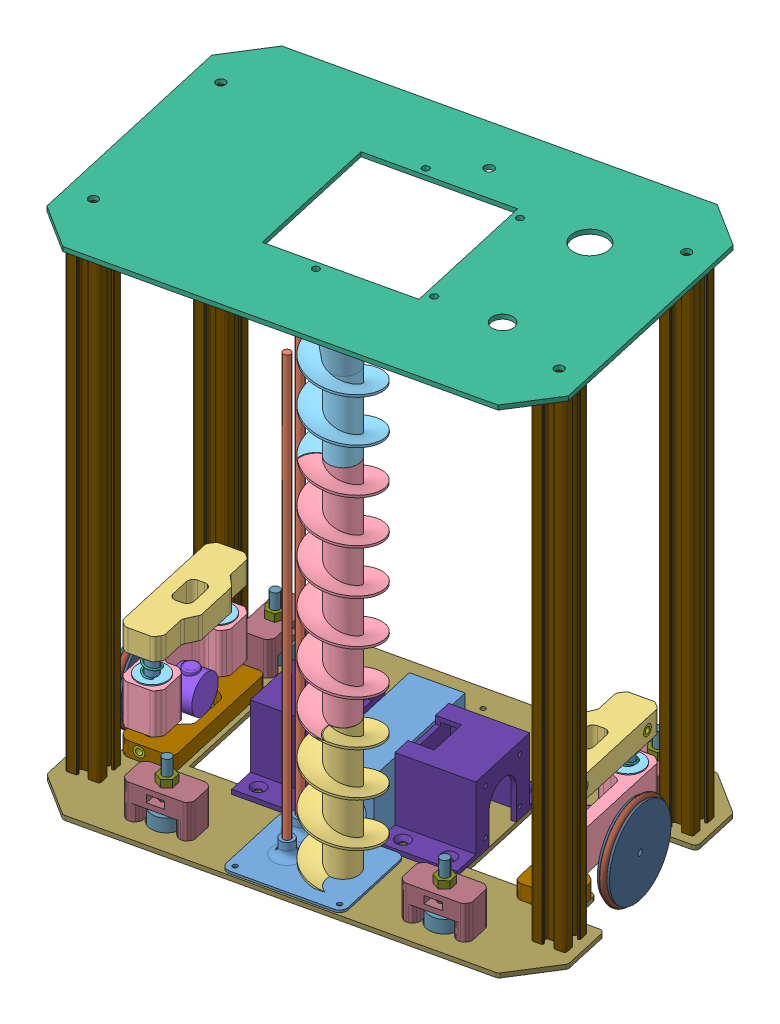
SolidWorks assembly Assemblage Robot 2 2023, configuration Défaut. Lengths in mm.
Overall size (336.15 361.9 260.69).
91 component instances, 24 part files, 26 mates.
Components (placement in the parent):
- Assemblage Base Roulante Robot 2-1: Assemblage Base Roulante Robot 2 [Défaut] at (-74.2511 215.8465 283.5318) size (336.15 94.74 260.69)
  - Assemblage Systeme Encodeurs-1: Assemblage Systeme Encodeurs [Défaut] at (-67.7934 10.2849 22.5399) size (62.28 94.74 89.05)
    - Axe_Support_Codeurs-1: Axe_Support_Codeurs [Défaut] at (-9.7273 -8.3238 48.8402) size (8 72 8)
    - Roulement linéaire-1: Roulement linéaire [Défaut] at (-9.7273 34.3589 48.8402) x (-0.971705 0 -0.236196) z (0 -1 0) size (15 15 24)
    - Support Ressort-1: Support Ressort [Défaut] at (-3.1044 51.6762 78.1001) x (0.220763 0 0.975327) z (-0.975327 0 0.220763) size (84.1 15.1 30.1)
    - Axe_Support_Codeurs-2: Axe_Support_Codeurs [Défaut] at (3.5185 -8.3238 107.3599) x (-0.166467 0 0.986047) z (-0.986047 0 -0.166467) size (8 72 8)
    - Roulement linéaire-2: Roulement linéaire [Défaut] at (3.5185 34.3589 107.3599) x (0.932325 0 -0.361623) z (0 -1 0) size (15 15 24)
    - Support Encodeurs-1: Support Encodeurs [Défaut] at (-3.1044 9.3589 78.1001) x (0.220763 0 0.975327) z (-0.975327 0 0.220763) size (84.1 37.8 24.1)
    - Rondelle M8-1: Rondelle M8 [Défaut] at (-9.7273 34.3589 48.8402) x (-0.837169 0 -0.546944) z (0 1 0) size (20 20 0.7)
    - Rondelle M8-2: Rondelle M8 [Défaut] at (3.5185 34.3589 107.3599) x (1 0 0) z (0 1 0) size (20 20 0.7)
    - Ressort M8-1: Ressort M8 [Défaut] at (3.5185 28.0864 107.3599) x (0.192743 0 -0.981249) z (0.981249 0 0.192743) size (12.72 24.18 12.45)
    - Ressort M8-2: Ressort M8 [Défaut] at (-9.7273 28.0864 48.8402) x (0.56484 0 0.8252) z (-0.8252 0 0.56484) size (12.72 24.18 12.45)
    - Insert M4-1: Insert M4 [Défaut] at (-21.1553 59.1762 52.7086) x (0.101832 0.887257 0.449894) z (0.975327 0 -0.220763) size (7 7 8)
    - Insert M4-4: Insert M4 [Défaut] at (-8.4614 59.1762 108.7899) x (0.099396 0.892908 0.439131) z (0.975327 0 -0.220763) size (7 7 8)
    - Codeurs Kuebler D24-2: Codeurs Kuebler D24 [Défaut] at (8.1118 8.8589 75.5613) x (-0.220763 0 -0.975327) z (-0.975327 0 0.220763) size (24 26 30.5)
    - Support Plaque Encodeurs-1: Support Plaque Encodeurs [Défaut] at (-3.1044 -10.3238 78.1001) x (0.220763 0 0.975327) z (-0.975327 0 0.220763) size (84 10 32)
    - Insert M4-5: Insert M4 [Défaut] at (6.1676 -4.8238 119.0638) x (-0.669085 -0.727591 0.151446) z (-0.220763 0 -0.975327) size (7 7 8)
    - Insert M4-6: Insert M4 [Défaut] at (-12.3765 -4.8238 37.1363) x (-0.897415 -0.391644 0.203128) z (0.220763 0 0.975327) size (7 7 8)
    - Insert M4-7: Insert M4 [Défaut] at (17.3015 -10.3238 109.3666) x (0.445123 0 0.895469) z (0 1 0) size (7 7 8)
    - Insert M4-8: Insert M4 [Défaut] at (1.8481 -10.3238 41.0937) x (0.956517 0 -0.291677) z (0 1 0) size (7 7 8)
    - Assemblage Roue Codeuse-1: Assemblage Roue Codeuse [Défaut] at (12.9164 -13.0885 115.5563) x (-0.212881 0.264817 -0.940507) z (0.975327 0 -0.220763) size (60 60 17)
      - Roue folle D56 BRS-1: Roue folle D56 BRS [Défaut] at (44.4504 10.553 -33.3566) size (56 56 17)
      - Joint Torique D52 T4 BRS-1: Joint Torique D52 T4 BRS [Défaut] at (44.4504 10.553 -29.8566) size (60 60 4)
  - Assemblage Systeme Encodeurs-2: Assemblage Systeme Encodeurs [Défaut] at (155.6849 10.2849 126.7509) x (-1 0 0) z (0 0 -1) size (62.28 94.74 89.05)
    - Axe_Support_Codeurs-1: Axe_Support_Codeurs [Défaut] at (-9.7273 -8.3238 48.8402) size (8 72 8)
    - Roulement linéaire-1: Roulement linéaire [Défaut] at (-9.7273 34.3589 48.8402) x (-0.971705 0 -0.236196) z (0 -1 0) size (15 15 24)
    - Support Ressort-1: Support Ressort [Défaut] at (-3.1044 51.6762 78.1001) x (0.220763 0 0.975327) z (-0.975327 0 0.220763) size (84.1 15.1 30.1)
    - Axe_Support_Codeurs-2: Axe_Support_Codeurs [Défaut] at (3.5185 -8.3238 107.3599) x (-0.166467 0 0.986047) z (-0.986047 0 -0.166467) size (8 72 8)
    - Roulement linéaire-2: Roulement linéaire [Défaut] at (3.5185 34.3589 107.3599) x (0.932325 0 -0.361623) z (0 -1 0) size (15 15 24)
    - Support Encodeurs-1: Support Encodeurs [Défaut] at (-3.1044 9.3589 78.1001) x (0.220763 0 0.975327) z (-0.975327 0 0.220763) size (84.1 37.8 24.1)
    - Rondelle M8-1: Rondelle M8 [Défaut] at (-9.7273 34.3589 48.8402) x (-0.837169 0 -0.546944) z (0 1 0) size (20 20 0.7)
    - Rondelle M8-2: Rondelle M8 [Défaut] at (3.5185 34.3589 107.3599) x (1 0 0) z (0 1 0) size (20 20 0.7)
    - Ressort M8-1: Ressort M8 [Défaut] at (3.5185 28.0864 107.3599) x (0.192743 0 -0.981249) z (0.981249 0 0.192743) size (12.72 24.18 12.45)
    - Ressort M8-2: Ressort M8 [Défaut] at (-9.7273 28.0864 48.8402) x (0.56484 0 0.8252) z (-0.8252 0 0.56484) size (12.72 24.18 12.45)
    - Insert M4-1: Insert M4 [Défaut] at (-21.1553 59.1762 52.7086) x (0.101832 0.887257 0.449894) z (0.975327 0 -0.220763) size (7 7 8)
    - Insert M4-4: Insert M4 [Défaut] at (-8.4614 59.1762 108.7899) x (0.099396 0.892908 0.439131) z (0.975327 0 -0.220763) size (7 7 8)
    - Codeurs Kuebler D24-2: Codeurs Kuebler D24 [Défaut] at (8.1118 8.8589 75.5613) x (-0.220763 0 -0.975327) z (-0.975327 0 0.220763) size (24 26 30.5)
    - Support Plaque Encodeurs-1: Support Plaque Encodeurs [Défaut] at (-3.1044 -10.3238 78.1001) x (0.220763 0 0.975327) z (-0.975327 0 0.220763) size (84 10 32)
    - Insert M4-5: Insert M4 [Défaut] at (6.1676 -4.8238 119.0638) x (-0.669085 -0.727591 0.151446) z (-0.220763 0 -0.975327) size (7 7 8)
    - Insert M4-6: Insert M4 [Défaut] at (-12.3765 -4.8238 37.1363) x (-0.897415 -0.391644 0.203128) z (0.220763 0 0.975327) size (7 7 8)
    - Insert M4-7: Insert M4 [Défaut] at (17.3015 -10.3238 109.3666) x (0.445123 0 0.895469) z (0 1 0) size (7 7 8)
    - Insert M4-8: Insert M4 [Défaut] at (1.8481 -10.3238 41.0937) x (0.956517 0 -0.291677) z (0 1 0) size (7 7 8)
    - Assemblage Roue Codeuse-1: Assemblage Roue Codeuse [Défaut] at (12.9164 -13.0885 115.5563) x (-0.212881 0.264817 -0.940507) z (0.975327 0 -0.220763) size (60 60 17)
      - Roue folle D56 BRS-1: Roue folle D56 BRS [Défaut] at (44.4504 10.553 -33.3566) size (56 56 17)
      - Joint Torique D52 T4 BRS-1: Joint Torique D52 T4 BRS [Défaut] at (44.4504 10.553 -29.8566) size (60 60 4)
  - plaque base roulante V3-3: plaque base roulante V3 [Défaut] at (-118.6656 -0.0389 34.5548) x (-0.220763 0 -0.975327) z (0 -1 0) size (199.5 299.5 3)
  - Assemblage Roue Porteuse V2-1: Assemblage Roue Porteuse V2 [Défaut] at (-23.5231 9.4567 127.8527) x (0.975327 0 -0.220763) z (0.220763 0 0.975327) size (40 48.37 20.68)
    - Support Bille porteuse V2-1: Support Bille porteuse V2 [Défaut] at (-2.1983 -9.4956 40) size (40 23 20)
    - Bille porteuse ALWAYE D12_7-1: Bille porteuse ALWAYE D12_7 [Défaut] at (-1.9483 -6.9983 40) x (-0.034703 0 0.999398) z (-0.999398 0 -0.034703) size (20 46.5 20)
    - Bille D12-1: Bille D12 [Défaut] at (-1.9483 -13.3717 40) x (-0.8229 0 0.568186) z (-0.568186 0 -0.8229) size (12 12 12)
    - Insert M4-1: Insert M4 [Défaut] at (-17.1983 -9.4956 40) x (1 0 0) z (0 1 0) size (7 7 8)
    - Insert M4-2: Insert M4 [Défaut] at (12.8017 -9.4956 40) x (1 0 0) z (0 1 0) size (7 7 8)
    - Ecrou M6-3: Ecrou M6 [Défaut] at (-1.9483 13.5044 40) x (0.999888 0 0.014972) z (-0.014972 0 0.999888) size (10 5 11.55)
    - Ecrou M6-4: Ecrou M6 [Défaut] at (-1.9483 5.0044 40) size (10 5 11.55)
  - Assemblage Roue Porteuse V2-2: Assemblage Roue Porteuse V2 [Défaut] at (-38.9948 9.4567 24.1596) x (0.220763 0 0.975327) z (-0.975327 0 0.220763) size (40 48.37 20.68)
    - Support Bille porteuse V2-1: Support Bille porteuse V2 [Défaut] at (-2.1983 -9.4956 40) size (40 23 20)
    - Bille porteuse ALWAYE D12_7-1: Bille porteuse ALWAYE D12_7 [Défaut] at (-1.9483 -6.9983 40) x (-0.034703 0 0.999398) z (-0.999398 0 -0.034703) size (20 46.5 20)
    - Bille D12-1: Bille D12 [Défaut] at (-1.9483 -13.3717 40) x (-0.8229 0 0.568186) z (-0.568186 0 -0.8229) size (12 12 12)
    - Insert M4-1: Insert M4 [Défaut] at (-17.1983 -9.4956 40) x (1 0 0) z (0 1 0) size (7 7 8)
    - Insert M4-2: Insert M4 [Défaut] at (12.8017 -9.4956 40) x (1 0 0) z (0 1 0) size (7 7 8)
    - Ecrou M6-3: Ecrou M6 [Défaut] at (-1.9483 13.5044 40) x (0.999888 0 0.014972) z (-0.014972 0 0.999888) size (10 5 11.55)
    - Ecrou M6-4: Ecrou M6 [Défaut] at (-1.9483 5.0044 40) size (10 5 11.55)
  - Assemblage Roue Porteuse V2-3: Assemblage Roue Porteuse V2 [Défaut] at (96.0903 9.4567 -10.9245) x (-0.220763 0 -0.975327) z (0.975327 0 -0.220763) size (40 48.37 20.68)
    - Support Bille porteuse V2-1: Support Bille porteuse V2 [Défaut] at (-2.1983 -9.4956 40) size (40 23 20)
    - Bille porteuse ALWAYE D12_7-1: Bille porteuse ALWAYE D12_7 [Défaut] at (-1.9483 -6.9983 40) x (-0.034703 0 0.999398) z (-0.999398 0 -0.034703) size (20 46.5 20)
    - Bille D12-1: Bille D12 [Défaut] at (-1.9483 -13.3717 40) x (-0.8229 0 0.568186) z (-0.568186 0 -0.8229) size (12 12 12)
    - Insert M4-1: Insert M4 [Défaut] at (-17.1983 -9.4956 40) x (1 0 0) z (0 1 0) size (7 7 8)
    - Insert M4-2: Insert M4 [Défaut] at (12.8017 -9.4956 40) x (1 0 0) z (0 1 0) size (7 7 8)
    - Ecrou M6-3: Ecrou M6 [Défaut] at (-1.9483 13.5044 40) x (0.999888 0 0.014972) z (-0.014972 0 0.999888) size (10 5 11.55)
    - Ecrou M6-4: Ecrou M6 [Défaut] at (-1.9483 5.0044 40) size (10 5 11.55)
  - Assemblage Roue Porteuse V2-4: Assemblage Roue Porteuse V2 [Défaut] at (132.0392 9.4567 92.6416) x (0.975327 0 -0.220763) z (0.220763 0 0.975327) size (40 48.37 20.68)
    - Support Bille porteuse V2-1: Support Bille porteuse V2 [Défaut] at (-2.1983 -9.4956 40) size (40 23 20)
    - Bille porteuse ALWAYE D12_7-1: Bille porteuse ALWAYE D12_7 [Défaut] at (-1.9483 -6.9983 40) x (-0.034703 0 0.999398) z (-0.999398 0 -0.034703) size (20 46.5 20)
    - Bille D12-1: Bille D12 [Défaut] at (-1.9483 -13.3717 40) x (-0.8229 0 0.568186) z (-0.568186 0 -0.8229) size (12 12 12)
    - Insert M4-1: Insert M4 [Défaut] at (-17.1983 -9.4956 40) x (1 0 0) z (0 1 0) size (7 7 8)
    - Insert M4-2: Insert M4 [Défaut] at (12.8017 -9.4956 40) x (1 0 0) z (0 1 0) size (7 7 8)
    - Ecrou M6-3: Ecrou M6 [Défaut] at (-1.9483 13.5044 40) x (0.999888 0 0.014972) z (-0.014972 0 0.999888) size (10 5 11.55)
    - Ecrou M6-4: Ecrou M6 [Défaut] at (-1.9483 5.0044 40) size (10 5 11.55)
  - Cage stepper-1: Cage stepper [Défaut] at (66.4906 42.9611 91.5863) x (0.220763 0 0.975327) z (0.975327 0 -0.220763) size (83 46 46.5)
  - Cage stepper-2: Cage stepper [Défaut] at (21.4008 42.9611 57.7045) x (-0.220763 0 -0.975327) z (-0.975327 0 0.220763) size (83 46 46.5)
- Profilé Aluminium Bosch Rexroth 20 x 20 x 335 mm-1: Profilé Aluminium Bosch Rexroth 20 x 20 x 335 mm [Défaut] at (112.9477 215.8076 385.2194) x (0.975327 0 -0.220763) z (0.220763 0 0.975327) size (20 335 20)
- Profilé Aluminium Bosch Rexroth 20 x 20 x 335 mm-2: Profilé Aluminium Bosch Rexroth 20 x 20 x 335 mm [Défaut] at (-173.5584 215.8076 331.1349) x (0.975327 0 -0.220763) z (0.220763 0 0.975327) size (20 335 20)
- Profilé Aluminium Bosch Rexroth 20 x 20 x 335 mm-3: Profilé Aluminium Bosch Rexroth 20 x 20 x 335 mm [Défaut] at (-147.9499 215.8076 444.2729) x (0.975327 0 -0.220763) z (0.220763 0 0.975327) size (20 335 20)
- Profilé Aluminium Bosch Rexroth 20 x 20 x 335 mm-4: Profilé Aluminium Bosch Rexroth 20 x 20 x 335 mm [Défaut] at (87.3392 215.8076 272.0814) x (0.975327 0 -0.220763) z (0.220763 0 0.975327) size (20 335 20)
- Support vis base-1: Support vis base [Défaut] at (-5.3308 215.8076 309.9731) x (0.220763 0 0.975327) z (0 1 0) size (150 70 41.5)
- Tige de guidage-1: Tige de guidage [Défaut] at (-28.1756 217.3076 431.0025) x (1 0 0) z (0 1 0) size (5 5 298.65)
- Tige de guidage-2: Tige de guidage [Défaut] at (-37.4675 217.3076 412.5998) x (1 0 0) z (0 1 0) size (5 5 298.65)
- P1 vis sans fin-1: P1 vis sans fin [Défaut] at (-0.995 552.3076 419.7238) x (1 0 0) z (0 -1 0) size (45.32 45.12 360)
- P2 vis sans fin-1: P2 vis sans fin [Défaut] at (-1.12 552.1076 419.5988) x (1 0 0) z (0 -1 0) size (45.32 45.12 360)
- P3 vis sans fin V.2-1: P3 vis sans fin V.2 [Défaut] at (-1.12 551.9076 419.5988) x (1 0 0) z (0 -1 0) size (45.32 45.05 360)
- Plaque LIDAR V.1-1: Plaque LIDAR V.1 [Défaut] at (132.3057 553.8076 398.2665) x (0.220763 0 0.975327) z (0 -1 0) size (199.5 299.5 3)
Mates (geometry in assembly coordinates):
- Coïncidente1: coincident aligned: circle of Assemblage Base Roulante Robot 2-1/plaque base roulante V3-3; circle of Profilé Aluminium Bosch Rexroth 20 x 20 x 335 mm-1
- Coïncidente2: coincident aligned: circle of Assemblage Base Roulante Robot 2-1/plaque base roulante V3-3; circle of Profilé Aluminium Bosch Rexroth 20 x 20 x 335 mm-3
- Coïncidente3: coincident aligned: circle of Assemblage Base Roulante Robot 2-1/plaque base roulante V3-3; circle of Profilé Aluminium Bosch Rexroth 20 x 20 x 335 mm-2
- Coïncidente4: coincident aligned: circle of Assemblage Base Roulante Robot 2-1/plaque base roulante V3-3; circle of Profilé Aluminium Bosch Rexroth 20 x 20 x 335 mm-4
- Parallèle1: parallel aligned: plane of Assemblage Base Roulante Robot 2-1/plaque base roulante V3-3 through (132.3059 212.8076 398.2678) normal (0.975327 0 -0.220763); plane of Profilé Aluminium Bosch Rexroth 20 x 20 x 335 mm-4 through (97.8652 550.8076 273.2874) normal (0.975327 0 -0.220763)
- Parallèle2: parallel aligned: plane of Assemblage Base Roulante Robot 2-1/plaque base roulante V3-3 through (132.3059 212.8076 398.2678) normal (0.975327 0 -0.220763); plane of Profilé Aluminium Bosch Rexroth 20 x 20 x 335 mm-1 through (123.4737 550.8076 386.4254) normal (0.975327 0 -0.220763)
- Parallèle3: parallel aligned: plane of Assemblage Base Roulante Robot 2-1/plaque base roulante V3-3 through (-192.9166 212.8076 318.0866) normal (-0.975327 0 0.220763); plane of Profilé Aluminium Bosch Rexroth 20 x 20 x 335 mm-2 through (-182.539 550.8076 336.7562) normal (-0.975327 0 0.220763)
- Parallèle4: parallel aligned: plane of Assemblage Base Roulante Robot 2-1/plaque base roulante V3-3 through (-192.9166 212.8076 318.0866) normal (-0.975327 0 0.220763); plane of Profilé Aluminium Bosch Rexroth 20 x 20 x 335 mm-3 through (-156.9305 550.8076 449.8942) normal (-0.975327 0 0.220763)
- Coïncidente9: coincident anti-aligned: plane of Assemblage Base Roulante Robot 2-1/plaque base roulante V3-3 through (-192.9166 215.8076 318.0866) normal (0 1 0); plane of Support vis base-1 through (-5.3308 215.8076 309.9731) normal (0 -1 0)
- Coaxiale1: concentric aligned: circle of Assemblage Base Roulante Robot 2-1/plaque base roulante V3-3; circle of Support vis base-1
- Coaxiale2: concentric aligned: circle of Assemblage Base Roulante Robot 2-1/plaque base roulante V3-3; circle of Support vis base-1
- Coaxiale3: concentric anti-aligned: circle of Support vis base-1; circle of Tige de guidage-1
- Coïncidente10: coincident anti-aligned: plane of Support vis base-1 through (-5.3308 217.3076 309.9731) normal (0 1 0); plane of Tige de guidage-1 through (-28.1756 217.3076 431.0025) normal (0 -1 0)
- Coaxiale4: concentric anti-aligned: circle of Support vis base-1; circle of Tige de guidage-2
- Coïncidente11: coincident anti-aligned: plane of Support vis base-1 through (-5.3308 217.3076 309.9731) normal (0 1 0); plane of Tige de guidage-2 through (-37.4675 217.3076 412.5998) normal (0 -1 0)
- Coïncidente12: coincident anti-aligned: plane of P2 vis sans fin-1 through (-6.12 442.1076 424.5988) normal (1 0 0); plane of P3 vis sans fin V.2-1 through (-6.12 442.1076 424.5988) normal (-1 0 0)
- Coïncidente13: coincident anti-aligned: plane of P2 vis sans fin-1 through (3.88 442.1076 424.5988) normal (0 0 -1); plane of P3 vis sans fin V.2-1 through (-6.12 442.1076 424.5988) normal (0 0 1)
- Coïncidente14: coincident anti-aligned: plane of P2 vis sans fin-1 through (-1.12 442.1076 419.5988) normal (0 1 0); plane of P3 vis sans fin V.2-1 through (-1.12 442.1076 419.5988) normal (0 -1 0)
- Coïncidente15: coincident anti-aligned: plane of P1 vis sans fin-1 through (3.88 327.1076 424.5988) normal (1 0 0); plane of P2 vis sans fin-1 through (3.88 327.1076 424.5988) normal (-1 0 0)
- Coïncidente16: coincident anti-aligned: plane of P1 vis sans fin-1 through (3.88 327.1076 424.5988) normal (0 0 1); plane of P2 vis sans fin-1 through (-6.12 327.1076 424.5988) normal (0 0 -1)
- Coïncidente17: coincident anti-aligned: plane of P1 vis sans fin-1 through (-0.995 327.1076 419.7238) normal (0 1 0); plane of P2 vis sans fin-1 through (-1.12 327.1076 419.5988) normal (0 -1 0)
- Coaxiale5: concentric anti-aligned: circle of Support vis base-1; circle of P1 vis sans fin-1
- Coïncidente18: coincident anti-aligned: plane of Support vis base-1 through (-5.3308 217.3076 309.9731) normal (0 1 0); plane of P1 vis sans fin-1 through (-0.995 217.3076 419.7238) normal (0 -1 0)
- Coaxiale8: concentric anti-aligned: circle of Profilé Aluminium Bosch Rexroth 20 x 20 x 335 mm-4; circle of Plaque LIDAR V.1-1
- Parallèle5: parallel aligned: plane of Profilé Aluminium Bosch Rexroth 20 x 20 x 335 mm-1 through (123.4737 550.8076 386.4254) normal (0.975327 0 -0.220763); plane of Plaque LIDAR V.1-1 through (132.3057 550.8076 398.2665) normal (0.975327 0 -0.220763)
- Coïncidente30: coincident anti-aligned: plane of Profilé Aluminium Bosch Rexroth 20 x 20 x 335 mm-1 through (112.9477 550.8076 385.2194) normal (0 1 0); plane of Plaque LIDAR V.1-1 through (132.3057 550.8076 398.2665) normal (0 -1 0)
